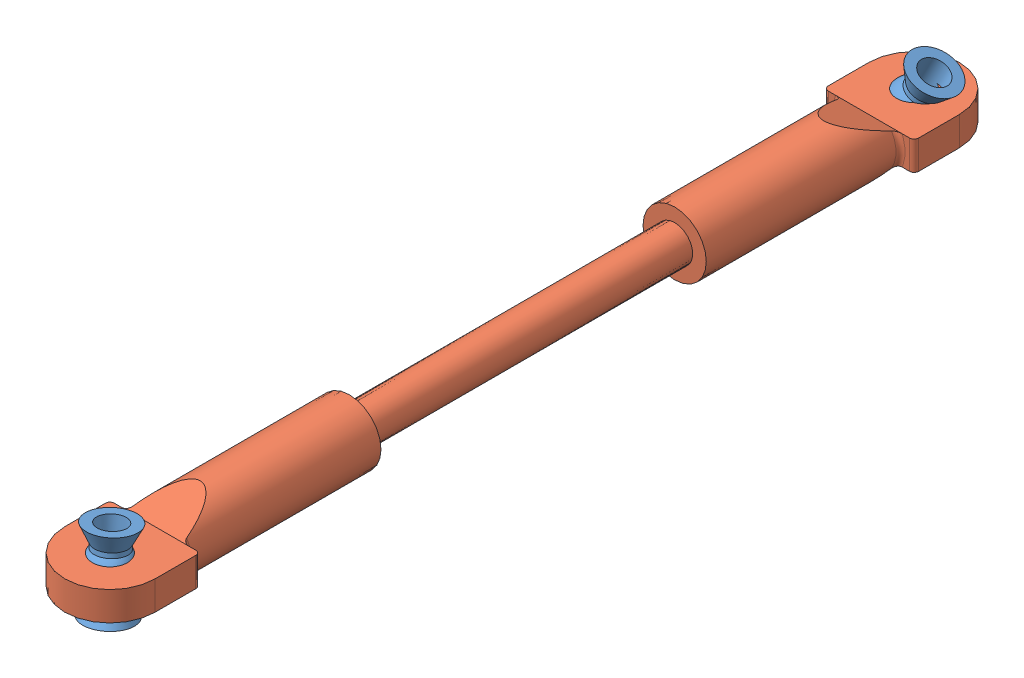
SolidWorks assembly TurnbuckleAssy_fore_steer, configuration Default. Lengths in mm.
Overall size (10 10.54 99).
3 component instances, 2 part files, 2 mates.
Components (placement in the parent):
- Turnbuckle Ball Spacer-1: Turnbuckle Ball Spacer [Default] at (-34.2894 8.6995 -27.7716) x (0.416171 0.900434 -0.12657) z (-0.208661 0.230055 0.950545) size (8.25 5.2 5.2)
- Turnbuckle Ball Spacer-2: Turnbuckle Ball Spacer [Default] at (-34.2894 8.6995 61.2284) x (-0.072069 0.990072 -0.120675) z (-0.090577 0.113993 0.989344) size (8.25 5.2 5.2)
- Turnbuckle Bar_fore_steer-1: Turnbuckle Bar_fore_steer [Default] at (-34.2894 8.6995 16.7284) size (10 7 99)
Mates (geometry in assembly coordinates):
- Concentric1: concentric: sphere of Turnbuckle Ball Spacer-2; sphere of Turnbuckle Bar_fore_steer-1
- Concentric2: concentric: sphere of Turnbuckle Ball Spacer-1; sphere of Turnbuckle Bar_fore_steer-1
